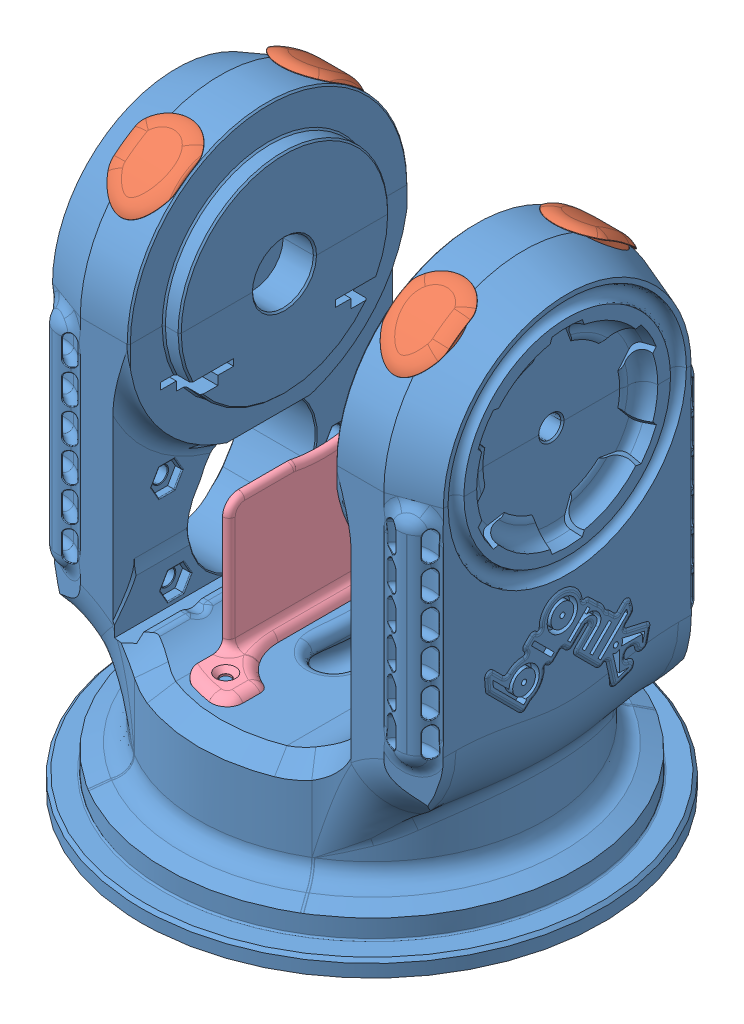
SolidWorks assembly 3.1 Structure, configuration Domyślna. Lengths in mm.
Overall size (145 196 145).
7 component instances, 4 part files, 15 mates.
Components (placement in the parent):
- 3.1.1 RotatingBase-1: 3.1.1 RotatingBase [Domyślna] at origin size (145 171 145)
- 3.1.2 Plug-1: 3.1.2 Plug [Domyślna] at (-43 152 25) size (21 18.06 23.49)
- 3.1.2 Plug-2: 3.1.2 Plug [Domyślna] at (43 152 -25) x (-1 0 0) z (0 0 -1) size (21 18.06 23.49)
- 3.1.2 Plug-3: 3.1.2 Plug [LustroDomyślna] at (-43 152 -25) size (21 18.06 23.49)
- 3.1.2 Plug-4: 3.1.2 Plug [LustroDomyślna] at (43 152 25) x (-1 0 0) z (0 0 -1) size (21 18.06 23.49)
- 3.1.4 Limiter-1: 3.1.4 Limiter [Domyślna] at (-21.6678 20 19.8979) x (0 0 1) z (1 0 0) size (15 45 15)
- 3.1.5 CableSeparator-1: 3.1.5 CableSeparator [Domyślna] at (0 43 0) size (21.21 42.77 89.34)
Mates (geometry in assembly coordinates):
- Koncentryczne15: concentric aligned: cylinder of 3.1.2 Plug-1 through (-43 500152 25) axis (0 -1 0) radius 9.2; cylinder of 3.1.1 RotatingBase-1 through (-43 171 25) axis (0 -1 0) radius 9.25
- Koncentryczne16: concentric anti-aligned: cylinder of 3.1.1 RotatingBase-1 through (0 127 0) axis (-1 0 0) radius 44; cylinder of 3.1.2 Plug-1 through (-54 127 0) axis (1 0 0) radius 44
- Koncentryczne20: concentric anti-aligned: cylinder of 3.1.1 RotatingBase-1 through (0 127 0) axis (1 0 0) radius 44; cylinder of 3.1.2 Plug-2 through (54 127 0) axis (-1 0 0) radius 44
- Koncentryczne21: concentric aligned: cylinder of 3.1.1 RotatingBase-1 through (43 171 -25) axis (0 -1 0) radius 9.25; cylinder of 3.1.2 Plug-2 through (43 500152 -25) axis (0 -1 0) radius 9.2
- Koncentryczne22: concentric anti-aligned: cylinder of 3.1.1 RotatingBase-1 through (0 127 0) axis (-1 0 0) radius 44; cylinder of 3.1.2 Plug-3 through (-54 127 0) axis (1 0 0) radius 44
- Koncentryczne23: concentric aligned: cylinder of 3.1.1 RotatingBase-1 through (-43 171 -25) axis (0 -1 0) radius 9.25; cylinder of 3.1.2 Plug-3 through (-43 500152 -25) axis (0 -1 0) radius 9.2
- Koncentryczne18: concentric anti-aligned: cylinder of 3.1.1 RotatingBase-1 through (0 127 0) axis (1 0 0) radius 44; cylinder of 3.1.2 Plug-4 through (54 127 0) axis (-1 0 0) radius 44
- Koncentryczne19: concentric aligned: cylinder of 3.1.1 RotatingBase-1 through (43 171 25) axis (0 -1 0) radius 9.25; cylinder of 3.1.2 Plug-4 through (43 500152 25) axis (0 -1 0) radius 9.2
- Wspólnie28: coordinate: point of 3.1.1 RotatingBase-1; point of assembly
- Wspólnie29: coincident anti-aligned: plane of 3.1.1 RotatingBase-1 through (0 20 19.8979) normal (0 0 1); plane of 3.1.4 Limiter-1 through (-21.6678 -25 19.8979) normal (0 0 -1)
- Wspólnie30: coincident anti-aligned: plane of 3.1.1 RotatingBase-1 through (-21.6678 20 0) normal (-1 0 0); plane of 3.1.4 Limiter-1 through (-21.6678 -25 19.8979) normal (1 0 0)
- Wspólnie31: coincident anti-aligned: plane of 3.1.1 RotatingBase-1 through (0 20 0) normal (0 -1 0); plane of 3.1.4 Limiter-1 through (-21.6678 20 19.8979) normal (0 1 0)
- Wspólnie32: coincident aligned: plane of 3.1.1 RotatingBase-1 through (0 43 0) normal (0 1 0); plane of 3.1.5 CableSeparator-1 through (0 43 0) normal (0 1 0)
- Wspólnie33: coincident aligned: plane of 3.1.5 CableSeparator-1 through (0 43 0) normal (0 0 1); plane of assembly through (0 0 0) normal (0 0 1)
- Wspólnie34: coincident aligned: plane of 3.1.5 CableSeparator-1 through (0 43 0) normal (1 0 0); plane of assembly through (0 0 0) normal (1 0 0)
